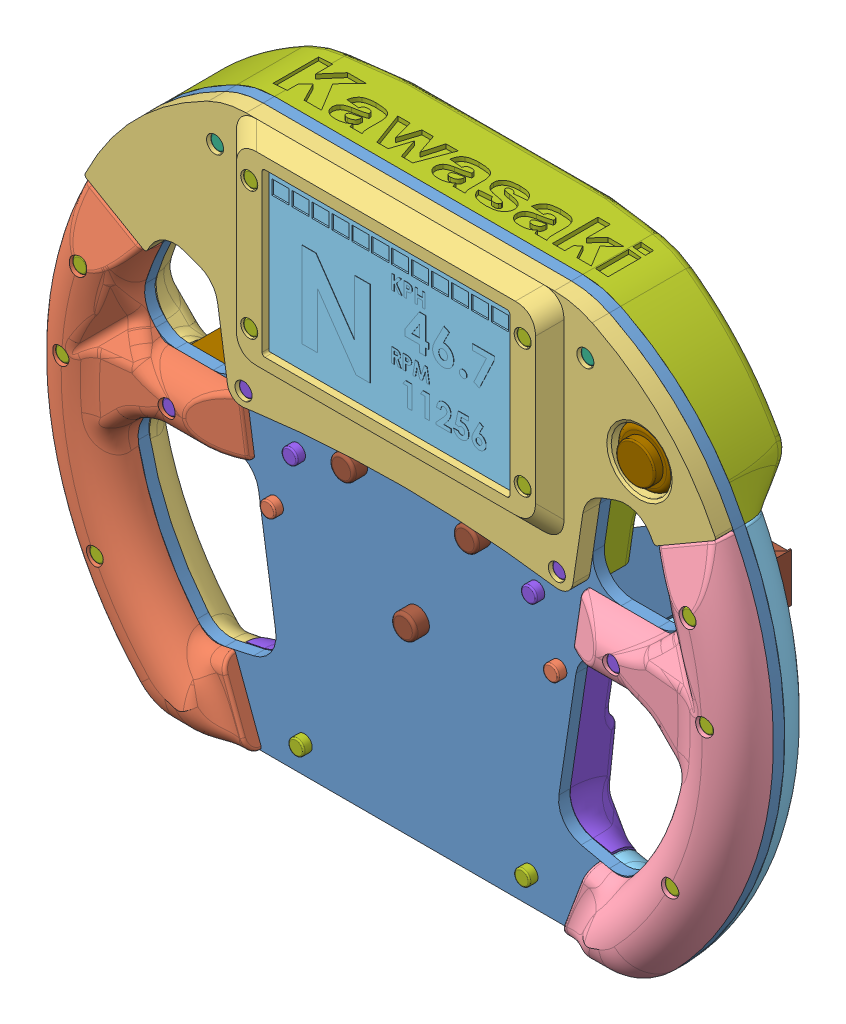
SolidWorks assembly RF019 SW Assem, configuration ﾃﾞﾌｫﾙﾄ. Lengths in mm.
Overall size (580 763.75 76.39).
97 component instances, 34 part files, 6 mates.
Components (placement in the parent):
- RF019 SWCP&G-1: RF019 SWCP&G [ﾃﾞﾌｫﾙﾄ] at (-208.5908 62.3494 534.2718) size (580 763.75 72.95)
  - RF019 SWCP kai-1: RF019 SWCP kai [ﾃﾞﾌｫﾙﾄ] at (-50.3349 -23.1318 252) size (250 250 4)
  - RF019 SWG kai LF-1: RF019 SWG kai LF [ﾃﾞﾌｫﾙﾄ] at (-50.3349 -23.1318 252) size (580 763.75 26.45)
  - RF019 SWG kai LR-1: RF019 SWG kai LR [ﾃﾞﾌｫﾙﾄ] at (-50.3349 -23.1318 248) size (580 763.75 28.68)
  - RF019 SWG kai RF-1: RF019 SWG kai RF [ﾃﾞﾌｫﾙﾄ] at (-50.3349 -23.1318 252) size (580 763.75 26.45)
  - RF019 SWG kai RR-1: RF019 SWG kai RR [ﾃﾞﾌｫﾙﾄ] at (-50.3349 -23.1318 248) size (580 763.75 29.22)
  - M3 Nat-1: M3 Nat [ﾃﾞﾌｫﾙﾄ] at (-157.3349 11.8682 237.1) x (0.998944 0.04595 0) z (0 0 1) size (5.64 6.34 2.4)
  - M3 Nat-2: M3 Nat [ﾃﾞﾌｫﾙﾄ] at (-163.3349 -18.1318 237.1) x (-0.539266 0.842136 0) z (0 0 1) size (5.64 6.34 2.4)
  - M3 Nat-3: M3 Nat [ﾃﾞﾌｫﾙﾄ] at (-151.3349 -73.1318 237.1) x (0.998944 0.04595 0) z (0 0 1) size (5.64 6.34 2.4)
  - M3 Nat-4: M3 Nat [ﾃﾞﾌｫﾙﾄ] at (56.6651 11.8682 237.1) x (0.998944 0.04595 0) z (0 0 1) size (5.64 6.34 2.4)
  - M3 Nat-5: M3 Nat [ﾃﾞﾌｫﾙﾄ] at (62.6651 -18.1318 237.1) x (0.539266 -0.842136 0) z (0 0 1) size (5.64 6.34 2.4)
  - M3 Nat-6: M3 Nat [ﾃﾞﾌｫﾙﾄ] at (50.6651 -73.1318 237.1) x (0.998944 0.04595 0) z (0 0 1) size (5.64 6.34 2.4)
  - M3 25 Bolt-1: M3 25 Bolt [ﾃﾞﾌｫﾙﾄ] at (56.6651 11.8682 263.5) x (0.995541 0.094327 0) z (0 0 -1) size (5.5 5.5 28)
  - M3 25 Bolt-2: M3 25 Bolt [ﾃﾞﾌｫﾙﾄ] at (-157.3349 11.8682 263.5) x (0.923728 0.383049 0) z (0 0 -1) size (5.5 5.5 28)
  - M3 25 Bolt-3: M3 25 Bolt [ﾃﾞﾌｫﾙﾄ] at (-163.3349 -18.1318 263.5) x (0.923728 0.383049 0) z (0 0 -1) size (5.5 5.5 28)
  - M3 25 Bolt-4: M3 25 Bolt [ﾃﾞﾌｫﾙﾄ] at (-151.3349 -73.1318 263.5) x (0.923728 0.383049 0) z (0 0 -1) size (5.5 5.5 28)
  - M3 25 Bolt-5: M3 25 Bolt [ﾃﾞﾌｫﾙﾄ] at (50.6651 -73.1318 263.5) x (0.923728 0.383049 0) z (0 0 -1) size (5.5 5.5 28)
  - M3 25 Bolt-6: M3 25 Bolt [ﾃﾞﾌｫﾙﾄ] at (62.6651 -18.1318 263.5) x (0.923728 0.383049 0) z (0 0 -1) size (5.5 5.5 28)
  - M3 20 Bolt-1: M3 20 Bolt [ﾃﾞﾌｫﾙﾄ] at (-128.3349 -18.1318 261) x (0.923728 0.383049 0) z (0 0 -1) size (5.5 5.5 23)
  - M3 20 Bolt-2: M3 20 Bolt [ﾃﾞﾌｫﾙﾄ] at (27.6651 -18.1318 261) x (0.923728 0.383049 0) z (0 0 -1) size (5.5 5.5 23)
  - RF018 Paddle Shift Adapt Switch-1: RF018 Paddle Shift Adapt Switch [ﾃﾞﾌｫﾙﾄ] at (33.6651 44.8682 240) x (0.308889 0.951098 0) z (0 0 1) size (20 23.54 26.8)
  - RF018 Spacer for PSA Switch-1: RF018 Spacer for PSA Switch [ﾃﾞﾌｫﾙﾄ] at (33.6651 44.8682 252) x (0.606194 0.795317 0) z (0 0 1) size (20.5 20.5 2)
  - M3 20 Bolt-3: M3 20 Bolt [ﾃﾞﾌｫﾙﾄ] at (-92.3349 -18.1318 255) x (0.583085 -0.812411 0) z (0 0 -1) size (5.5 5.5 23)
  - M3 20 Bolt-4: M3 20 Bolt [ﾃﾞﾌｫﾙﾄ] at (-8.3349 -18.1318 255) x (0.923728 0.383049 0) z (0 0 -1) size (5.5 5.5 23)
  - M3 25 Bolt-7: M3 25 Bolt [ﾃﾞﾌｫﾙﾄ] at (-89.9626 -105.3898 255) x (0.923728 0.383049 0) z (0 0 -1) size (5.5 5.5 28)
  - M3 25 Bolt-8: M3 25 Bolt [ﾃﾞﾌｫﾙﾄ] at (-10.7072 -105.3898 255) x (0.923728 0.383049 0) z (0 0 -1) size (5.5 5.5 28)
  - M5 20 Bolt-1: M5 20 Bolt [ﾃﾞﾌｫﾙﾄ] at (-28.6843 -10.6318 257) x (-0.388877 -0.92129 0) z (0 0 -1) size (8.5 8.5 20)
  - M5 20 Bolt-2: M5 20 Bolt [ﾃﾞﾌｫﾙﾄ] at (-71.9855 -10.6318 257) x (0.990277 0.139111 0) z (0 0 -1) size (8.5 8.5 20)
  - M5 20 Bolt-3: M5 20 Bolt [ﾃﾞﾌｫﾙﾄ] at (-50.3349 -48.1318 257) x (0.943817 0.330469 0) z (0 0 -1) size (8.5 8.5 20)
  - Quick Release 1-1: Quick Release 1 [ﾃﾞﾌｫﾙﾄ] at (-54.124 -40.0834 338) x (-0.5 -0.866025 0) z (0 0 -1) size (80.66 80.66 55)
    - 1-1-1: 1-1 [ﾃﾞﾌｫﾙﾄ] at (-16.575 5.1943 90) size (59.95 55.8 55)
    - 1-2-1: 1-2 [ﾃﾞﾌｫﾙﾄ] at (-16.575 5.1943 102) x (-0.986103 -0.166135 0) z (0 0 1) size (70 70 43)
    - 1-3-1: 1-3 [ﾃﾞﾌｫﾙﾄ] at (-16.575 5.1943 145) x (-0.997775 -0.066677 0) z (0 0 -1) size (40 40 20)
    - 1-5-1: 1-5 [ﾃﾞﾌｫﾙﾄ] at (-16.575 5.1943 134.5) x (-0.836075 -0.548615 0) z (0 0 -1) size (25 25 10)
    - 1-4-1: 1-4 [ﾃﾞﾌｫﾙﾄ] at (-23.9223 -4.9184 137) size (5 5 5)
    - 1-4-2: 1-4 [ﾃﾞﾌｫﾙﾄ] at (-16.575 -7.3057 137) x (0.757505 -0.002014 -0.652826) z (0.259947 -0.91637 0.304457) size (5 5 5)
    - 1-4-4: 1-4 [ﾃﾞﾌｫﾙﾄ] at (-9.2277 -4.9184 137) x (0.59978 -0.145312 0.78686) z (-0.610771 0.552153 0.567525) size (5 5 5)
    - 1-4-5: 1-4 [ﾃﾞﾌｫﾙﾄ] at (-4.6868 1.3316 137) x (0.883022 0.321394 -0.34202) z (0.418989 -0.211471 0.883022) size (5 5 5)
    - 1-4-6: 1-4 [ﾃﾞﾌｫﾙﾄ] at (-28.4632 1.3316 137) x (0.720478 0.501888 -0.47856) z (0.592115 -0.085992 0.801253) size (5 5 5)
    - 1-4-7: 1-4 [ﾃﾞﾌｫﾙﾄ] at (-4.6868 9.057 137) x (0.586824 0.492404 -0.642788) z (0.790379 -0.175893 0.586824) size (5 5 5)
    - 1-4-12: 1-4 [ﾃﾞﾌｫﾙﾄ] at (-9.2277 15.307 137) x (0.37191 0.671322 -0.6411) z (0.907926 -0.119274 0.401802) size (5 5 5)
    - 1-4-13: 1-4 [ﾃﾞﾌｫﾙﾄ] at (-16.575 17.6943 137) x (0.144729 0.779036 -0.610046) z (0.980991 -0.032428 0.191322) size (5 5 5)
    - 1-4-16: 1-4 [ﾃﾞﾌｫﾙﾄ] at (-23.9223 15.307 137) x (-0.090859 0.870583 -0.48356) z (0.993983 0.109103 0.00966) size (5 5 5)
    - 1-4-17: 1-4 [ﾃﾞﾌｫﾙﾄ] at (-28.4632 9.057 137) x (-0.407074 0.843286 -0.350941) z (0.912107 0.354897 -0.205205) size (5 5 5)
    - Spring 1-1: Spring 1 [ﾃﾞﾌｫﾙﾄ] at (-16.575 5.1943 116) size (37.17 37.65 10)
    - Spring 2-1: Spring 2 [ﾃﾞﾌｫﾙﾄ] at (-16.575 5.1943 104) size (22.6 22.92 21.5)
  - M5 Nat-1: M5 Nat [ﾃﾞﾌｫﾙﾄ] at (-28.6843 -10.6318 239) x (0.511027 -0.859565 0) z (0 0 1) size (8.32 9.21 4)
  - M5 Nat-2: M5 Nat [ﾃﾞﾌｫﾙﾄ] at (-71.9855 -10.6318 239) x (0.959837 -0.280558 0) z (0 0 1) size (8.32 9.21 4)
  - M5 Nat-3: M5 Nat [ﾃﾞﾌｫﾙﾄ] at (-50.3349 -48.1318 239) x (-0.606129 -0.795367 0) z (0 0 1) size (8.32 9.21 4)
  - M3 15 Bolt-1: M3 15 Bolt [ﾃﾞﾌｫﾙﾄ] at (-100.0734 -38.1318 255) x (0.923728 0.383049 0) z (0 0 -1) size (5.5 5.5 18)
  - M3 15 Bolt-2: M3 15 Bolt [ﾃﾞﾌｫﾙﾄ] at (-0.5964 -38.1318 255) x (-0.918666 0.395034 0) z (0 0 -1) size (5.5 5.5 18)
- RF019 SWMB&AM-1: RF019 SWMB&AM [ﾃﾞﾌｫﾙﾄ] at (-18.0909 -6.7841 28.025) size (580 763.75 44)
  - RF019 SWMB kai-1: RF019 SWMB kai [ﾃﾞﾌｫﾙﾄ] at (-240.8348 46.0016 758.2468) size (580 763.75 11)
  - M3 25 Bolt-1: M3 25 Bolt [ﾃﾞﾌｫﾙﾄ] at (-288.8348 136.0016 768.7468) x (-0.923728 -0.383049 0) z (0 0 -1) size (5.5 5.5 28)
  - M3 25 Bolt-2: M3 25 Bolt [ﾃﾞﾌｫﾙﾄ] at (-192.8348 136.0016 768.7468) x (0.997282 -0.073685 0) z (0 0 -1) size (5.5 5.5 28)
  - M3 25 Bolt-3: M3 25 Bolt [ﾃﾞﾌｫﾙﾄ] at (-192.8348 91.0016 768.7468) x (0.997282 -0.073685 0) z (0 0 -1) size (5.5 5.5 28)
  - M3 25 Bolt-4: M3 25 Bolt [ﾃﾞﾌｫﾙﾄ] at (-288.8348 91.0016 768.7468) x (-0.37219 -0.928157 0) z (0 0 -1) size (5.5 5.5 28)
  - RF018 Spacer for SWMB[M3 9]-1: RF018 Spacer for SWMB[M3 9] [ﾃﾞﾌｫﾙﾄ] at (-288.8348 91.0016 749.2468) x (0.899926 -0.436043 0) z (0 0 1) size (8 8 9)
  - RF018 Spacer for SWMB[M3 9]-2: RF018 Spacer for SWMB[M3 9] [ﾃﾞﾌｫﾙﾄ] at (-192.8348 91.0016 749.2468) size (8 8 9)
  - RF018 Spacer for SWMB[M3 9]-3: RF018 Spacer for SWMB[M3 9] [ﾃﾞﾌｫﾙﾄ] at (-288.8348 136.0016 749.2468) size (8 8 9)
  - RF018 Spacer for SWMB[M3 9]-4: RF018 Spacer for SWMB[M3 9] [ﾃﾞﾌｫﾙﾄ] at (-192.8348 136.0016 749.2468) x (0.695312 -0.718708 0) z (0 0 1) size (8 8 9)
  - RF019 AC kai Display-1: RF019 AC kai Display [ﾃﾞﾌｫﾙﾄ] at (-240.8348 118.5016 747.2468) size (105 73 36.1)
  - M3 Nat-1: M3 Nat [ﾃﾞﾌｫﾙﾄ] at (-192.8348 136.0016 744.8468) x (0.713875 0.700273 0) z (0 0 1) size (5.64 6.34 2.4)
  - M3 Nat-2: M3 Nat [ﾃﾞﾌｫﾙﾄ] at (-192.8348 91.0016 744.8468) size (5.64 6.34 2.4)
  - M3 Nat-3: M3 Nat [ﾃﾞﾌｫﾙﾄ] at (-288.8348 91.0016 744.8468) size (5.64 6.34 2.4)
  - M3 Nat-4: M3 Nat [ﾃﾞﾌｫﾙﾄ] at (-288.8348 136.0016 744.8468) size (5.64 6.34 2.4)
  - M3 35 Bolt-1: M3 35 Bolt [ﾃﾞﾌｫﾙﾄ] at (-305.8348 136.0016 763.2468) x (0.923728 0.383049 0) z (0 0 -1) size (5.5 5.5 38)
  - M3 35 Bolt-2: M3 35 Bolt [ﾃﾞﾌｫﾙﾄ] at (-175.8348 136.0016 763.2468) x (0.923728 0.383049 0) z (0 0 -1) size (5.5 5.5 38)
  - M3 20 Bolt-1: M3 20 Bolt [ﾃﾞﾌｫﾙﾄ] at (-295.8348 66.0016 763.2468) x (0.923728 0.383049 0) z (0 0 -1) size (5.5 5.5 23)
  - M3 20 Bolt-2: M3 20 Bolt [ﾃﾞﾌｫﾙﾄ] at (-185.8348 66.0016 763.2468) x (0.923728 0.383049 0) z (0 0 -1) size (5.5 5.5 23)
- RF019 SWB&PSM-1: RF019 SWB&PSM [ﾃﾞﾌｫﾙﾄ] at (-205.6299 58.6483 503.0766) size (250 250 58.49)
  - RF019 SWB kai B1-1: RF019 SWB kai B1 [ﾃﾞﾌｫﾙﾄ] at (-53.2958 -19.4307 279.1952) size (250 250 58.49)
  - RF019 SWB kai B3-1: RF019 SWB kai B3 [ﾃﾞﾌｫﾙﾄ] at (-53.2958 -19.4307 279.1952) size (250 250 48.2)
  - RF019 SWB PSMB2L kai-1: RF019 SWB PSMB2L kai [ﾃﾞﾌｫﾙﾄ] at (-53.2958 -19.4307 279.1952) size (250 250 48.15)
  - RF019 SWB PSMB2R kai-1: RF019 SWB PSMB2R kai [ﾃﾞﾌｫﾙﾄ] at (-53.2958 -19.4307 279.1952) size (250 250 48.15)
  - RF018 IDEC Switch-1: RF018 IDEC Switch [ﾃﾞﾌｫﾙﾄ] at (-124.6708 -14.4307 243.1952) x (0 1 0) z (0 0 -1) size (17 23 38.5)
  - RF018 IDEC Switch-2: RF018 IDEC Switch [ﾃﾞﾌｫﾙﾄ] at (18.0792 -14.4307 243.1952) x (0 -1 0) z (0 0 -1) size (17 23 38.5)
  - RF019 CC-1: RF019 CC [ﾃﾞﾌｫﾙﾄ] at (-53.2958 30.039 257.1952) x (-1 0 0) z (0 0 -1) size (45 16 22)
  - M3 Nat-1: M3 Nat [ﾃﾞﾌｫﾙﾄ] at (-3.5573 -34.4307 268.7952) x (0.998944 0.04595 0) z (0 0 1) size (5.64 6.34 2.4)
  - M3 Nat-2: M3 Nat [ﾃﾞﾌｫﾙﾄ] at (-13.6813 -101.7767 261.7952) x (0.998944 0.04595 0) z (0 0 1) size (5.64 6.34 2.4)
  - M3 Nat-3: M3 Nat [ﾃﾞﾌｫﾙﾄ] at (11.7042 70.5693 254.7952) x (0.998944 0.04595 0) z (0 0 1) size (5.64 6.34 2.4)
  - M3 Nat-4: M3 Nat [ﾃﾞﾌｫﾙﾄ] at (-103.0343 -34.4307 268.7952) x (0.998944 0.04595 0) z (0 0 1) size (5.64 6.34 2.4)
  - M3 Nat-5: M3 Nat [ﾃﾞﾌｫﾙﾄ] at (-108.2958 0.5693 268.7952) x (0.998944 0.04595 0) z (0 0 1) size (5.64 6.34 2.4)
  - M3 Nat-6: M3 Nat [ﾃﾞﾌｫﾙﾄ] at (1.7042 0.5693 268.7952) x (0.998944 0.04595 0) z (0 0 1) size (5.64 6.34 2.4)
  - M3 Nat-7: M3 Nat [ﾃﾞﾌｫﾙﾄ] at (-118.2958 70.5693 254.7952) x (0.998944 0.04595 0) z (0 0 1) size (5.64 6.34 2.4)
  - M3 Nat-8: M3 Nat [ﾃﾞﾌｫﾙﾄ] at (-92.9103 -101.7767 261.7952) x (0.998944 0.04595 0) z (0 0 1) size (5.64 6.34 2.4)
  - M3 Nat-9: M3 Nat [ﾃﾞﾌｫﾙﾄ] at (-11.2958 -14.4307 265.7952) x (0.459678 0.888086 0) z (0 0 1) size (5.64 6.34 2.4)
  - M3 Nat-10: M3 Nat [ﾃﾞﾌｫﾙﾄ] at (-95.2958 -14.4307 265.7952) x (0.459678 0.888086 0) z (0 0 1) size (5.64 6.34 2.4)
  - M3 Nat-11: M3 Nat [ﾃﾞﾌｫﾙﾄ] at (24.7042 -14.4307 273.7952) x (0.998944 0.04595 0) z (0 0 1) size (5.64 6.34 2.4)
  - M3 Nat-12: M3 Nat [ﾃﾞﾌｫﾙﾄ] at (-131.2958 -14.4307 273.7952) x (0.998944 0.04595 0) z (0 0 1) size (5.64 6.34 2.4)
  - M2 Nat-1: M2 Nat [ﾃﾞﾌｫﾙﾄ] at (-72.2958 30.039 250.5952) x (0.998944 0.04595 0) z (0 0 1) size (4.1 4.61 1.6)
  - M2 Nat-2: M2 Nat [ﾃﾞﾌｫﾙﾄ] at (-34.2958 30.039 252.1952) x (0.998944 -0.04595 0) z (0 0 -1) size (4.1 4.61 1.6)
  - M2 8 Bolt-1: M2 8 Bolt [ﾃﾞﾌｫﾙﾄ] at (-34.2958 30.039 259.1952) x (-0.923728 -0.383049 0) z (0 0 -1) size (3.8 3.8 10)
  - M2 8 Bolt-2: M2 8 Bolt [ﾃﾞﾌｫﾙﾄ] at (-72.2958 30.039 259.1952) x (-0.923728 -0.383049 0) z (0 0 -1) size (3.8 3.8 10)
  - RF019 SC kai-1: RF019 SC kai [ﾃﾞﾌｫﾙﾄ] at (-53.2958 -80.7767 276.1952) x (-1 0 0) z (0 0 -1) size (67 40 14.5)
  - RF018 Spacer for Shifter Circle[Φ5 3]-1: RF018 Spacer for Shifter Circle[Φ5 3] [ﾃﾞﾌｫﾙﾄ] at (-82.2958 -88.7767 276.1952) x (0.815194 -0.579188 0) z (0 0 1) size (10 10 2)
  - RF018 Spacer for Shifter Circle[Φ5 3]-2: RF018 Spacer for Shifter Circle[Φ5 3] [ﾃﾞﾌｫﾙﾄ] at (-24.2958 -88.7767 276.1952) x (0.906897 -0.421352 0) z (0 0 1) size (10 10 2)
Mates (geometry in assembly coordinates):
- 同心円1: concentric aligned: cylinder of RF019 SWCP&G-1/RF019 SWCP kai-1 through (-323.9257 129.2175 776.2718) axis (0 0 1) radius 1.75; cylinder of RF019 SWMB&AM-1/M3 35 Bolt-1 through (-323.9257 129.2175 753.2718) axis (0 0 1) radius 1.5
- 同心円2: concentric aligned: cylinder of RF019 SWCP&G-1/RF019 SWCP kai-1 through (-193.9257 129.2175 776.2718) axis (0 0 1) radius 1.75; cylinder of RF019 SWMB&AM-1/M3 35 Bolt-2 through (-193.9257 129.2175 753.2718) axis (0 0 1) radius 1.5
- 一致1: coincident anti-aligned: plane of RF019 SWCP&G-1/RF019 SWCP kai-1 through (-258.9257 39.2175 786.2718) normal (0 0 1); plane of RF019 SWMB&AM-1/RF019 SWMB kai-1 through (-258.9257 39.2175 786.2718) normal (0 0 -1)
- 同心円3: concentric aligned: cylinder of RF019 SWMB&AM-1/M3 35 Bolt-2 through (-193.9257 129.2175 753.2718) axis (0 0 1) radius 1.5; cylinder of RF019 SWB&PSM-1/RF019 SWB kai B1-1 through (-193.9257 129.2175 732.2718) axis (0 0 1) radius 1.75
- 同心円4: concentric aligned: cylinder of RF019 SWMB&AM-1/M3 35 Bolt-1 through (-323.9257 129.2175 753.2718) axis (0 0 1) radius 1.5; cylinder of RF019 SWB&PSM-1/RF019 SWB kai B1-1 through (-323.9257 129.2175 732.2718) axis (0 0 1) radius 1.75
- 一致2: coincident anti-aligned: plane of RF019 SWCP&G-1/RF019 SWCP kai-1 through (-258.9257 39.2175 782.2718) normal (0 0 -1); plane of RF019 SWB&PSM-1/RF019 SWB kai B1-1 through (-258.9257 39.2175 782.2718) normal (0 0 1)
